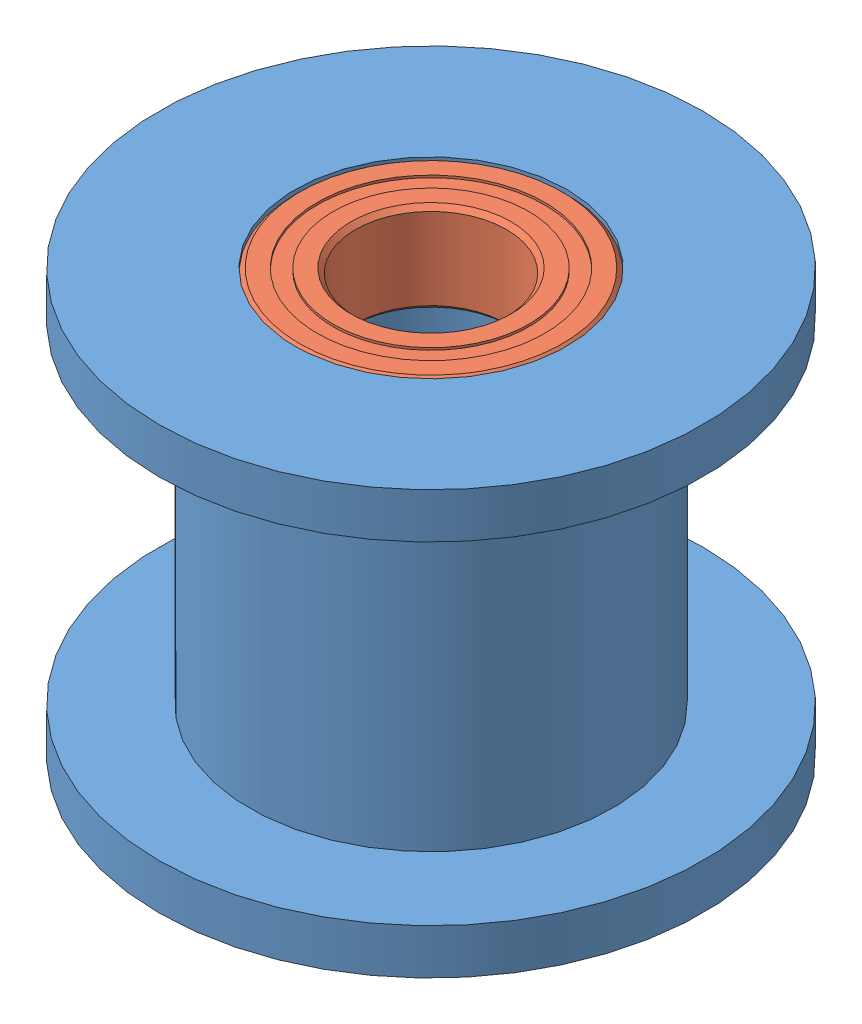
SolidWorks assembly 1037396, configuration Default. Lengths in mm.
Overall size (18 14 18).
3 component instances, 2 part files, 3 mates.
Components (placement in the parent):
- 1037396-IDLER PULLEY-1: 1037396-IDLER PULLEY [Default] at origin size (18 14 18)
- 1037396-95-2Z BEARING, 9 mm OD, 5 mm ID, 3 mm WIDTH-1: 1037396-95-2Z BEARING, 9 mm OD, 5 mm ID, 3 mm WIDTH [DEFAULT] at (0 5.5 0) x (0.843163 0 0.537658) z (0 1 0) size (9 9 3)
- 1037396-95-2Z BEARING, 9 mm OD, 5 mm ID, 3 mm WIDTH-2: 1037396-95-2Z BEARING, 9 mm OD, 5 mm ID, 3 mm WIDTH [DEFAULT] at (0 -5.5 0) x (-0.843163 0 -0.537658) z (0 -1 0) size (9 9 3)
Mates (geometry in assembly coordinates):
- Coincident1: coordinate: point of 1037396-IDLER PULLEY-1; point of assembly
- Concentric1: concentric anti-aligned: cylinder of 1037396-IDLER PULLEY-1 through (0 5.5 0) axis (0 -1 0) radius 4.5; cylinder of 1037396-95-2Z BEARING, 9 mm OD, 5 mm ID, 3 mm WIDTH-1 through (0 7 0) axis (0 1 0) radius 2.5
- Coincident2: coincident anti-aligned: plane of 1037396-IDLER PULLEY-1 through (0 4 0) normal (0 1 0); plane of 1037396-95-2Z BEARING, 9 mm OD, 5 mm ID, 3 mm WIDTH-1 through (1.4248 4 -2.2344) normal (0 -1 0)
